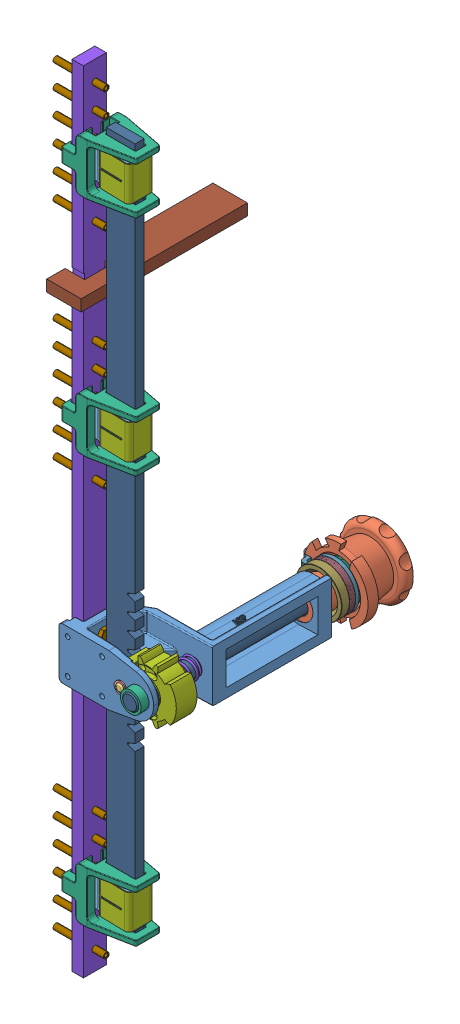
SolidWorks assembly HM 30kV 30A L131 23.44.885, configuration Default. Lengths in mm.
Overall size (123.25 689 227.57).
70 component instances, 29 part files, 0 mates.
Components (placement in the parent):
- HM 30kV 30A L131.stp-1: HM 30kV 30A L131.stp [Default] at origin size (123.25 689 227.57)
  - PALIER L=131 Pignon 20 dents 5 Positions Pas de 21_54__30-63A - 1 _tage.stp-1: PALIER L=131 Pignon 20 dents 5 Positions Pas de 21_54__30-63A - 1 _tage.stp [Default] at (0 44.6942 -66) x (1 0 0) z (0 0 -1) size (102 47.66 209)
    - 43500_02-43500-131 Palier L=131.stp-1: 43500_02-43500-131 Palier L=131.stp [Default] at origin size (85.75 46.98 184)
      - 43500_02-43500-131_PALIER L=131.stp-1: 43500_02-43500-131_PALIER L=131.stp [Default] at origin size (85.75 46.98 152)
      - 43519_PRESSE-ETOUPE.stp-1: 43519_PRESSE-ETOUPE.stp [Default] at (-22.5 22.5 130) x (1 0 0) z (0 -1 0) size (27.1 44 27)
    - 56142_Pion d'indexation avec rondelle Z5.stp-1: 56142_Pion d'indexation avec rondelle Z5.stp [Default] at (-38 22.5 -37) size (10 10 19)
      - 56142_Pion d'indexation serti.stp-1: 56142_Pion d'indexation serti.stp [Default] at origin size (8 8 19)
      - Rondelle Plate Z5.stp-1: Rondelle Plate Z5.stp [Default] at (0 0 -17) x (0 -1 0) z (0 0 -1) size (10 10 1)
    - 56068_Patin bleu_HZ_HM.stp-1: 56068_Patin bleu_HZ_HM.stp [Default] at (-67.75 14 -33) x (0 0 1) z (0 1 0) size (15 17 17)
    - bague c14-18-14.stp-1: bague c14-18-14.stp [Default] at (-22.5 22.5 -47) x (0 1 0) z (1 0 0) size (22 14 22)
    - 26826-20-5-21_PIGNON 20 Dents 5 Positions Pas de 21.stp-1: 26826-20-5-21_PIGNON 20 Dents 5 Positions Pas de 21.stp [Default] at (-22.5 22.5 -46) x (0 -1 0) z (0 0 1) size (47.66 49.5 25)
    - 26845-2_Ressort de rappel H=15.stp-1: 26845-2_Ressort de rappel H=15.stp [Default] at (-22.5 22.5 -8) x (0.992336 0.123569 0) z (0 0 1) size (18.3 18.31 16.7)
    - VIS_H_M5_25.stp-1: VIS_H_M5_25.stp [Default] at (-74.75 35 -33) x (0 -0.5 -0.866025) z (1 0 0) size (8.07 9.3 28.5)
    - VIS_H_M5_25.stp-2: VIS_H_M5_25.stp [Default] at (-74.75 10 -33) x (0 -0.5 -0.866025) z (1 0 0) size (8.07 9.3 28.5)
    - 43504-209_AXE_L=209_HM.stp-1: 43504-209_AXE_L=209_HM.stp [Default] at (-22.5 22.5 135) size (14.03 14 209)
    - Ecrou autofrein_ M5.stp-1: Ecrou autofrein_ M5.stp [Default] at (-91.75 10 -33) x (0 -1 0) z (1 0 0) size (11.8 11.8 6.2)
    - Ecrou autofrein_ M5.stp-2: Ecrou autofrein_ M5.stp [Default] at (-91.75 35 -33) x (0 -1 0) z (1 0 0) size (11.8 11.8 6.2)
  - 43168_TETE 5 POSITIONS  Pas de 21.stp-1: 43168_TETE 5 POSITIONS  Pas de 21.stp [Default] at (-22.5 22.1942 -169) x (-1 0 0) z (0 0 -1) size (65.5 60 62.57)
    - 20210_SERRE JOINT_CA.stp-1: 20210_SERRE JOINT_CA.stp [Default] at (0 0 7) x (0 -1 0) z (-1 0 0) size (40 7 40)
    - 20161_Rondelle.stp-1: 20161_Rondelle.stp [Default] at (0 0 8) x (0 1 0) z (1 0 0) size (40 1 40)
    - 20161_Rondelle.stp-2: 20161_Rondelle.stp [Default] at (0 0 9) x (0 -1 0) z (-1 0 0) size (40 1 40)
    - 20161_Rondelle.stp-3: 20161_Rondelle.stp [Default] at (0 0 10) x (0 1 0) z (1 0 0) size (40 1 40)
    - 20161_Rondelle.stp-4: 20161_Rondelle.stp [Default] at (0 0 11) x (0 -1 0) z (-1 0 0) size (40 1 40)
    - 20188_bague de positionnement pour bouton cadenassable.stp-1: 20188_bague de positionnement pour bouton cadenassable.stp [Default] at (0 0 12) size (55.75 40.5 20)
    - 20139_ECROU.stp-1: 20139_ECROU.stp [Default] at (0 0 22) x (0 1 0) z (0 0 -1) size (35 32.09 7.09)
    - joint r11 _cras_.stp-1: joint r11 _cras_.stp [Default] at (0 0 12.5284) x (0 1 0) z (0 0 1) size (18 18 2)
    - joint r11 _cras_.stp-2: joint r11 _cras_.stp [Default] at (0 0 20.4716) x (0 -1 0) z (0 0 -1) size (18 18 2)
    - 20157_BAGUE 2 JOINTS_CA.stp-1: 20157_BAGUE 2 JOINTS_CA.stp [Default] at (0 0 20.75) x (0 1 0) z (0 0 1) size (20 20 4)
    - CIRCLIPS_848.020.09_TETE 43167.stp-1: CIRCLIPS_848.020.09_TETE 43167.stp [Default] at (0 0 24.75) x (0 -1 0) z (0 0 1) size (20 19.78 1)
    - 43508_JOINT_HM.stp-1: 43508_JOINT_HM.stp [Default] at (0 0 27) x (1 0 0) z (0 -1 0) size (26 6 26)
    - 43505_5 POS_54__PAS=21.stp-1: 43505_5 POS_54__PAS=21.stp [Default] at (0 0 13) x (-1 0 0) z (0 0 1) size (60 60 46.74)
    - 20161_Rondelle.stp-5: 20161_Rondelle.stp [Default] at (0 0 11) x (0 -1 0) z (1 0 0) size (40 1 40)
    - RONDELLE FIBRE _6.stp-1: RONDELLE FIBRE _6.stp [Default] at (0 0 59) x (-1 0 0) z (0 0 -1) size (10 10 1)
    - VIS_CBL_M6_25.stp-1: VIS_CBL_M6_25.stp [Default] at (0 0 59) x (-1 0 0) z (0 0 1) size (12 12 28.57)
  - 43515 + 26462.stp-1: 43515 + 26462.stp [Default] at (-77.95 -176.8058 -40.5) x (0 -1 0) z (0 0 1) size (45.04 59.04 35.05)
    - 43515_CONTACT MOBILE _ 3.1_HM.stp-1: 43515_CONTACT MOBILE _ 3.1_HM.stp [Default] at (-4.5 35.9 14.45) x (1 0 0) z (0 0 -1) size (34.04 35.02 7)
    - 43515_CONTACT MOBILE _ 3.1_HM.stp-2: 43515_CONTACT MOBILE _ 3.1_HM.stp [Default] at (-38.5 35.9 0.55) x (-1 0 0) z (0 0 1) size (34.04 35.02 7)
    - 26462_GUIDE HM.stp-1: 26462_GUIDE HM.stp [Default] at (-44 -16.3 7.5) x (0 0 1) z (0 1 0) size (35.05 45.04 59.04)
    - 26461_Ressort dessin_ en position travail_HM.stp-1: 26461_Ressort dessin_ en position travail_HM.stp [Default] at (-21.5 37.1 7.55) x (0 0 1) z (0 1 0) size (22.21 30 27.4)
  - 43515 + 26462.stp-2: 43515 + 26462.stp [Default] at (-77.95 221.1942 -25.5) x (0 1 0) z (0 0 -1) size (45.04 59.04 35.05)
    - 43515_CONTACT MOBILE _ 3.1_HM.stp-1: 43515_CONTACT MOBILE _ 3.1_HM.stp [Default] at (-4.5 35.9 14.45) x (1 0 0) z (0 0 -1) size (34.04 35.02 7)
    - 43515_CONTACT MOBILE _ 3.1_HM.stp-2: 43515_CONTACT MOBILE _ 3.1_HM.stp [Default] at (-38.5 35.9 0.55) x (-1 0 0) z (0 0 1) size (34.04 35.02 7)
    - 26462_GUIDE HM.stp-1: 26462_GUIDE HM.stp [Default] at (-44 -16.3 7.5) x (0 0 1) z (0 1 0) size (35.05 45.04 59.04)
    - 26461_Ressort dessin_ en position travail_HM.stp-1: 26461_Ressort dessin_ en position travail_HM.stp [Default] at (-21.5 37.1 7.55) x (0 0 1) z (0 1 0) size (22.21 30 27.4)
  - 43515 + 26462.stp-3: 43515 + 26462.stp [Default] at (-77.95 373.1942 -40.5) x (0 -1 0) z (0 0 1) size (45.04 59.04 35.05)
    - 43515_CONTACT MOBILE _ 3.1_HM.stp-1: 43515_CONTACT MOBILE _ 3.1_HM.stp [Default] at (-4.5 35.9 14.45) x (1 0 0) z (0 0 -1) size (34.04 35.02 7)
    - 43515_CONTACT MOBILE _ 3.1_HM.stp-2: 43515_CONTACT MOBILE _ 3.1_HM.stp [Default] at (-38.5 35.9 0.55) x (-1 0 0) z (0 0 1) size (34.04 35.02 7)
    - 26462_GUIDE HM.stp-1: 26462_GUIDE HM.stp [Default] at (-44 -16.3 7.5) x (0 0 1) z (0 1 0) size (35.05 45.04 59.04)
    - 26461_Ressort dessin_ en position travail_HM.stp-1: 26461_Ressort dessin_ en position travail_HM.stp [Default] at (-21.5 37.1 7.55) x (0 0 1) z (0 1 0) size (22.21 30 27.4)
  - BFP44885-5.stp-1: BFP44885-5.stp [Default] at (-91.75 464.1942 -43) x (-1 0 0) z (0 0 -1) size (10 689 20)
  - 26856-B44_HZ-HM_CONTACT FIXE__5.stp-1: 26856-B44_HZ-HM_CONTACT FIXE__5.stp [Default] at (-71.75 231.1942 -33) x (0 1 0) z (0 0 1) size (5 44 5)
  - 26856-B44_HZ-HM_CONTACT FIXE__5.stp-2: 26856-B44_HZ-HM_CONTACT FIXE__5.stp [Default] at (-71.75 -123.8058 -33) x (0 1 0) z (0 0 1) size (5 44 5)
  - 26856-B44_HZ-HM_CONTACT FIXE__5.stp-3: 26856-B44_HZ-HM_CONTACT FIXE__5.stp [Default] at (-71.75 426.1942 -33) x (0 1 0) z (0 0 1) size (5 44 5)
  - 26856-B44_HZ-HM_CONTACT FIXE__5.stp-4: 26856-B44_HZ-HM_CONTACT FIXE__5.stp [Default] at (-71.75 405.1942 -33) x (0 1 0) z (0 0 1) size (5 44 5)
  - 26856-B44_HZ-HM_CONTACT FIXE__5.stp-5: 26856-B44_HZ-HM_CONTACT FIXE__5.stp [Default] at (-71.75 447.1942 -33) x (0 1 0) z (0 0 1) size (5 44 5)
  - 26856-B44_HZ-HM_CONTACT FIXE__5.stp-6: 26856-B44_HZ-HM_CONTACT FIXE__5.stp [Default] at (-71.75 384.1942 -33) x (0 1 0) z (0 0 1) size (5 44 5)
  - BMP44885.stp-1: BMP44885.stp [Default] at (-42.75 421.6942 -37) x (0 0 -1) z (1 0 0) size (8 604 25)
  - 26856-B44_HZ-HM_CONTACT FIXE__5.stp-7: 26856-B44_HZ-HM_CONTACT FIXE__5.stp [Default] at (-71.75 252.1942 -33) x (0 1 0) z (0 0 1) size (5 44 5)
  - 26856-B44_HZ-HM_CONTACT FIXE__5.stp-8: 26856-B44_HZ-HM_CONTACT FIXE__5.stp [Default] at (-71.75 -102.8058 -33) x (0 1 0) z (0 0 1) size (5 44 5)
  - 26856-B44_HZ-HM_CONTACT FIXE__5.stp-9: 26856-B44_HZ-HM_CONTACT FIXE__5.stp [Default] at (-71.75 -165.8058 -33) x (0 1 0) z (0 0 1) size (5 44 5)
  - 26856-B44_HZ-HM_CONTACT FIXE__5.stp-10: 26856-B44_HZ-HM_CONTACT FIXE__5.stp [Default] at (-71.75 210.1942 -33) x (0 1 0) z (0 0 1) size (5 44 5)
  - 26856-B44_HZ-HM_CONTACT FIXE__5.stp-11: 26856-B44_HZ-HM_CONTACT FIXE__5.stp [Default] at (-71.75 189.1942 -33) x (0 1 0) z (0 0 1) size (5 44 5)
  - 26856-B44_HZ-HM_CONTACT FIXE__5.stp-12: 26856-B44_HZ-HM_CONTACT FIXE__5.stp [Default] at (-71.75 -144.8058 -33) x (0 1 0) z (0 0 1) size (5 44 5)
  - 26856-B44_HZ-HM_CONTACT FIXE__5.stp-13: 26856-B44_HZ-HM_CONTACT FIXE__5.stp [Default] at (-71.75 363.1942 -33) x (0 1 0) z (0 0 1) size (5 44 5)
  - 26856-B44_HZ-HM_CONTACT FIXE__5.stp-14: 26856-B44_HZ-HM_CONTACT FIXE__5.stp [Default] at (-71.75 -186.8058 -33) x (0 1 0) z (0 0 1) size (5 44 5)
  - 26856-B44_HZ-HM_CONTACT FIXE__5.stp-15: 26856-B44_HZ-HM_CONTACT FIXE__5.stp [Default] at (-71.75 168.1942 -33) x (0 1 0) z (0 0 1) size (5 44 5)
  - 26856-B44_HZ-HM_CONTACT FIXE__5.stp-16: 26856-B44_HZ-HM_CONTACT FIXE__5.stp [Default] at (-71.75 342.1942 -33) x (0 1 0) z (0 0 1) size (5 44 5)
  - 26856-B44_HZ-HM_CONTACT FIXE__5.stp-17: 26856-B44_HZ-HM_CONTACT FIXE__5.stp [Default] at (-71.75 -207.8058 -33) x (0 1 0) z (0 0 1) size (5 44 5)
  - 26856-B44_HZ-HM_CONTACT FIXE__5.stp-18: 26856-B44_HZ-HM_CONTACT FIXE__5.stp [Default] at (-71.75 147.1942 -33) x (0 1 0) z (0 0 1) size (5 44 5)
  - 43532_A=145.stp-1: 43532_A=145.stp [Default] at (-98.75 302.1942 4.1583) x (-1 0 0) z (0 -1 0) size (30 145 10)
